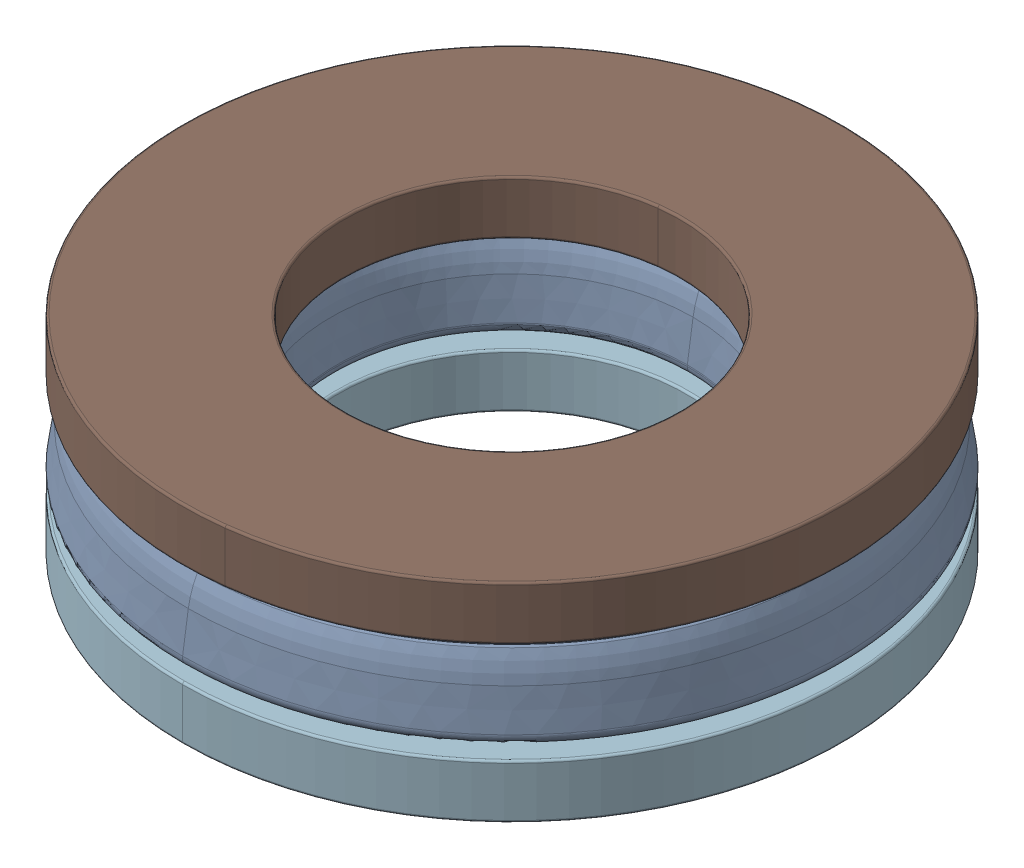
SolidWorks assembly 8mm_ID_15.5mm_OD_thrust_bearing, configuration Default. Lengths in mm.
Overall size (17.52 4.96 17.52).
12 component instances, 4 part files, 2 mates.
Components (placement in the parent):
- 1613-0516-0008 carriage_1-1: 1613-0516-0008 carriage_1 [Default] at (-23.0253 -4.8501 14.8236) size (15.72 1.83 15.72)
- 1613-0516-0008 ball-1: 1613-0516-0008 ball [Default] at (-28.8255 -3.9351 16.4353) size (3 3 3)
- 1613-0516-0008 ball-2: 1613-0516-0008 ball [Default] at (-26.4325 -3.9351 19.7866) x (0.766044 0 -0.642788) z (0.642788 0 0.766044) size (3 3 3)
- 1613-0516-0008 ball-3: 1613-0516-0008 ball [Default] at (-22.4452 -3.9351 20.8156) x (0.173648 0 -0.984808) z (0.984808 0 0.173648) size (3 3 3)
- 1613-0516-0008 ball-4: 1613-0516-0008 ball [Default] at (-18.7293 -3.9351 19.0408) x (-0.5 0 -0.866025) z (0.866025 0 -0.5) size (3 3 3)
- 1613-0516-0008 ball-5: 1613-0516-0008 ball [Default] at (-17.0236 -3.9351 15.2928) x (-0.939693 0 -0.34202) z (0.34202 0 -0.939693) size (3 3 3)
- 1613-0516-0008 ball-6: 1613-0516-0008 ball [Default] at (-18.1261 -3.9351 11.3252) x (-0.939693 0 0.34202) z (-0.34202 0 -0.939693) size (3 3 3)
- 1613-0516-0008 ball-7: 1613-0516-0008 ball [Default] at (-21.521 -3.9351 8.9945) x (-0.5 0 0.866025) z (-0.866025 0 -0.5) size (3 3 3)
- 1613-0516-0008 ball-8: 1613-0516-0008 ball [Default] at (-25.6197 -3.9351 9.3913) x (0.173648 0 0.984808) z (-0.984808 0 0.173648) size (3 3 3)
- 1613-0516-0008 ball-9: 1613-0516-0008 ball [Default] at (-28.5045 -3.9351 12.3299) x (0.766044 0 0.642788) z (-0.642788 0 0.766044) size (3 3 3)
- 1613-0516-0008 washer (8mm ID x 15.72mm OD)_1-2: 1613-0516-0008 washer (8mm ID x 15.72mm OD)_1 [Default] at (-23.0253 -1.4551 14.8236) x (0.992523 0 -0.12206) z (-0.12206 0 -0.992523) size (15.72 1.28 15.72)
- 1613-0516-0008 washer (8.3mm ID x 15.72mm OD)_1-1: 1613-0516-0008 washer (8.3mm ID x 15.72mm OD)_1 [Default] at (-23.0253 -6.4151 14.8236) size (15.72 1.28 15.72)
Mates (geometry in assembly coordinates):
- Concentric1: concentric: cylinder of 1613-0516-0008 washer (8mm ID x 15.72mm OD)_1-2 through (-23.0253 -2.7351 14.8236) axis (0 1 0) radius 7.86; cylinder of 1613-0516-0008 washer (8.3mm ID x 15.72mm OD)_1 - Copy-1 through (-23.0253 -5.1351 14.8236) axis (0 -1 0) radius 7.86
- Distance1: distance = 4.96 mm anti-aligned: plane of 1613-0516-0008 washer (8.3mm ID x 15.72mm OD)_1 - Copy-1 through (-23.0253 -6.4151 14.8236) normal (0 -1 0); plane of 1613-0516-0008 washer (8mm ID x 15.72mm OD)_1-2 through (-23.0253 -1.4551 14.8236) normal (0 1 0)
